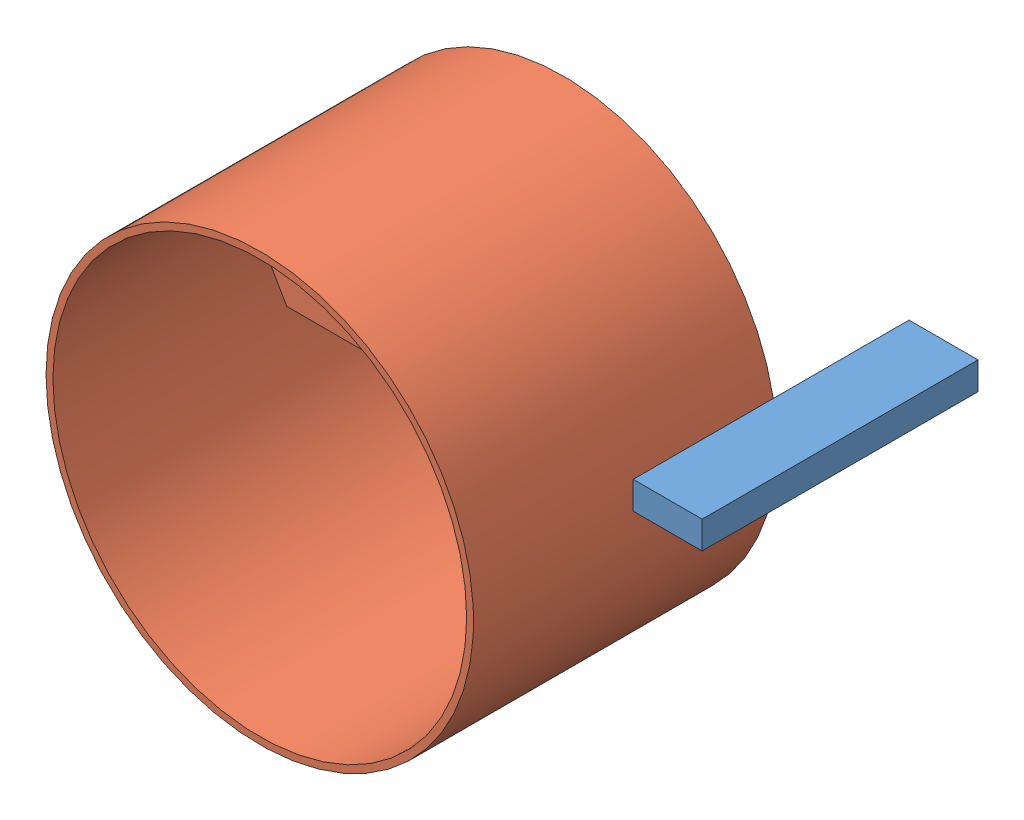
SolidWorks assembly 装配体3, configuration Default. Lengths in mm.
Overall size (365.76 310 310).
2 component instances, 2 part files, 0 mates.
Components (placement in the parent):
- bed2-1: bed2 [默认] at (77.0979 122.9954 21.3181) size (50 20 200)
- gantry-1: gantry [默认] at (-83.6572 95.9973 221.3181) size (310 310 220)
